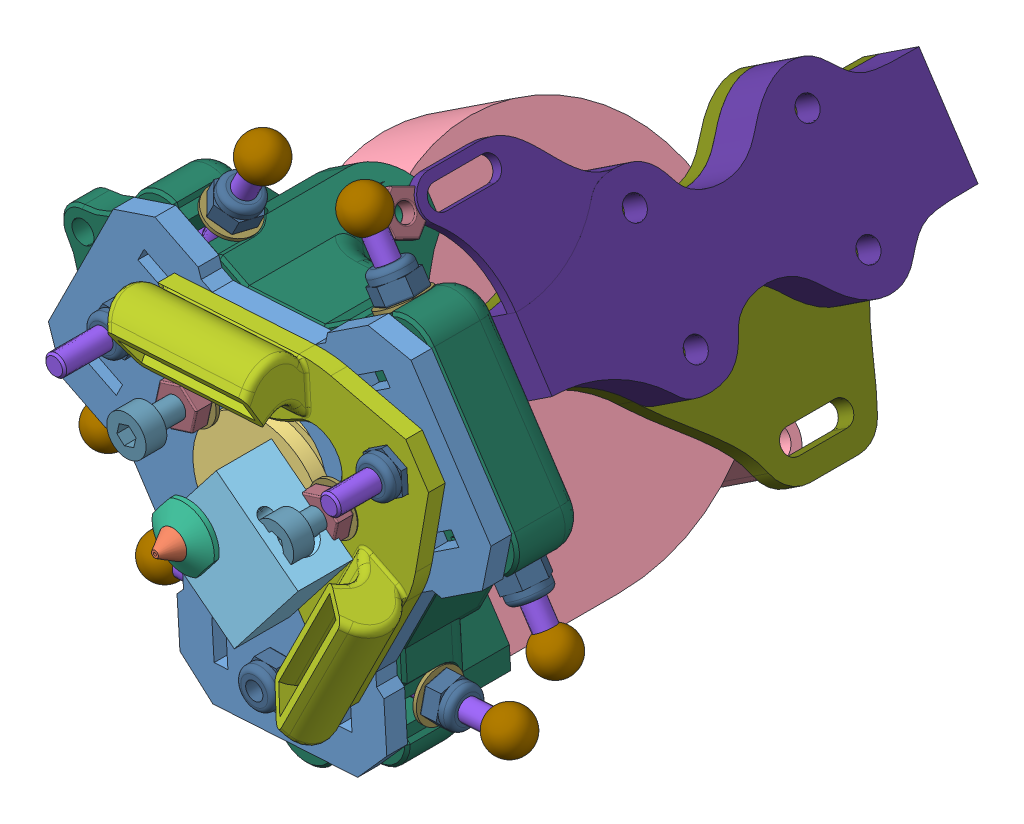
SolidWorks assembly head, configuration Default. Lengths in mm.
Overall size (84.31 86.45 108.8).
49 component instances, 17 part files, 158 mates.
Components (placement in the parent):
- 1223-2: 1223 [Default] at (-3 0 -7.9081) x (-0.551258 0.834335 0) z (0 0 -1) size (64.19 57.24 3)
- 1179-1: 1179 [Default] at (-3 0 -13.9069) x (-1 0 0) z (0 0 1) size (4.4 4.4 23)
- 1136-1: 1136 [Default<As Machined>] at (-3 0 -5.9081) x (0.828844 -0.559479 0) z (0 0 1) size (19 19 18.8)
- 1194-1: 1194 [Default] at (-16.6907 -11.2059 -51.2081) x (0 0 1) z (0.834335 0.551258 0) size (51 51 15)
- heater-block-1: heater-block [Default] at (-3 0 4.2951) x (0.788829 -0.614612 0) z (0 0 -1) size (15 15 8)
- 1180-2: 1180 [Default] at (-3 0 6.4951) x (-0.788829 0.614612 0) z (0 0 1) size (8 9 2.2)
- 1247-1: 1247 [Default] at (-3 0 -7.9081) x (0.551258 -0.834335 0) z (0 0 1) size (51.6 29.13 11.32)
- 242-8: 242 [Default] at (21.7023 4.3356 -15.9081) x (0.722555 0.477403 0.5) z (-0.551258 0.834335 0) size (5.7 5.7 19)
- 242-7: 242 [Default] at (10.6771 21.0223 -15.9081) x (0.698006 0.461183 0.547813) z (0.551258 -0.834335 0) size (5.7 5.7 19)
- 242-9: 242 [Default] at (8.3673 -22.3559 -15.9081) x (0.052165 -0.864453 0.5) z (-0.998184 -0.060235 0) size (5.7 5.7 19)
- 242-10: 242 [Default] at (-11.5964 -23.5606 -15.9081) x (0.052165 -0.864453 -0.5) z (0.998184 0.060235 0) size (5.7 5.7 19)
- 242-11: 242 [Default] at (-28.0444 1.3336 -15.9081) x (0 0 -1) z (0.446927 0.894571 0) size (5.7 5.7 19)
- 242-12: 242 [Default] at (-19.1059 19.225 -15.9081) x (0.774721 -0.38705 -0.5) z (-0.446927 -0.894571 0) size (5.7 5.7 19)
- 1191-1: 1191 [Default] at (2.4083 33.5373 -15.9081) x (0.551258 -0.834335 0) z (0 0 1) size (5.6 6 6)
- 1191-2: 1191 [Default] at (29.9711 -8.1795 -15.9081) x (-0.551258 0.834335 0) z (0.685911 0.453192 0.569336) size (5.6 6 6)
- 1191-3: 1191 [Default] at (-12.402 32.6436 -15.9081) x (-0.446927 -0.894571 0) z (-0.081785 0.04086 0.995812) size (5.6 6 6)
- 1191-4: 1191 [Default] at (-34.7483 -12.085 -15.9081) x (0.446927 0.894571 0) z (0 0 1) size (5.6 6 6)
- 1191-5: 1191 [Default] at (-26.5692 -24.4641 -15.9081) x (0.998184 0.060235 0) z (0 0 1) size (5.6 6 6)
- 1191-6: 1191 [Default] at (23.34 -21.4523 -15.9081) x (-0.998184 -0.060235 0) z (-0.007976 0.132169 0.991195) size (5.6 6 6)
- 204-1: 204 [Default] at (7.9208 25.194 -15.9081) x (-0.799834 -0.528462 -0.284593) z (-0.551258 0.834335 0) size (6.35 5.5 4)
- 204-2: 204 [Default] at (-16.8712 23.6979 -15.9081) x (0.188731 -0.09429 -0.977492) z (0.446927 0.894571 0) size (6.35 5.5 4)
- 204-3: 204 [Default] at (-30.279 -3.1392 -15.9081) x (-0.882358 0.440825 0.164675) z (-0.446927 -0.894571 0) size (6.35 5.5 4)
- 204-4: 204 [Default] at (-16.5873 -23.8618 -15.9081) x (0.059542 -0.986684 0.151356) z (-0.998184 -0.060235 0) size (6.35 5.5 4)
- 204-5: 204 [Default] at (13.3582 -22.0547 -15.9081) x (-0.057745 0.956908 -0.284593) z (0.998184 0.060235 0) size (6.35 5.5 4)
- 204-7: 204 [Default] at (24.4586 0.1639 -15.9081) x (0.566441 0.374256 0.734218) z (0.551258 -0.834335 0) size (6.35 5.5 4)
- 112-2: 112 [Default] at (-32.6899 3.3929 -32.2081) x (-0.535208 0.810044 0.239542) z (-0.834335 -0.551258 0) size (5.7 5.7 28)
- 212-1: 212 [Default] at (-10.4258 18.1031 -32.2081) x (0.051802 -0.078403 -0.995575) z (0.834335 0.551258 0) size (7 7 0.5)
- 258-4: 258 [Default] at (-10.0086 18.3788 -32.2081) x (0.548202 -0.829711 -0.105137) z (0.834335 0.551258 0) size (6.35 5.5 2.4)
- 257-3: 257 [Default] at (8.3082 4.0156 0.1632) x (0.976142 0.217134 0) z (0 0 1) size (5.7 5.7 15)
- 212-3: 212 [Default] at (8.3082 4.0156 -5.9081) size (7 7 0.5)
- 257-4: 257 [Default] at (-12.1317 7.7854 1.0837) x (-0.974821 0.22299 0) z (0 0 1) size (5.7 5.7 15)
- 212-4: 212 [Default] at (-12.1317 7.7854 -5.9081) size (7 7 0.5)
- 242-1: 242 [Default] at (-23.5751 10.2793 -12.9081) x (0.934462 0.356064 0) z (0 0 -1) size (5.7 5.7 19)
- 242-2: 242 [Default] at (16.1897 12.6789 -12.9081) x (-0.951162 0.308691 0) z (0 0 -1) size (5.7 5.7 19)
- 242-3: 242 [Default] at (-1.6146 -22.9582 -21.908) x (0.622999 -0.782222 0) z (0 0 -1) size (5.7 5.7 19)
- 204-8: 204 [Default] at (-1.6146 -22.9582 -7.9081) size (6.35 5.5 4)
- 204-9: 204 [Default] at (16.1897 12.6789 -7.1081) x (0.060235 -0.998184 0) z (0 0 1) size (6.35 5.5 4)
- 204-10: 204 [Default] at (-23.5751 10.2793 -7.9081) size (6.35 5.5 4)
- 258-6: 258 [Default] at (8.3082 4.0156 -3.0081) x (-0.214989 -0.976616 0) z (0 0 -1) size (6.35 5.5 2.4)
- 258-7: 258 [Default] at (-12.1317 7.7854 -3.0081) x (-0.214989 -0.976616 0) z (0 0 -1) size (6.35 5.5 2.4)
- 1301-1: 1301 [Default] at (-3 0 -10.9081) x (-0.551258 0.834335 0) z (0 0 -1) size (65.4 57.84 25.8)
- 212-7: 212 [Default] at (8.1965 24.7768 -15.9081) x (-0.761571 -0.503181 0.408433) z (-0.551258 0.834335 0) size (7 7 0.5)
- 212-8: 212 [Default] at (-17.0947 23.2506 -15.9081) x (-0.091855 0.045891 0.994714) z (0.446927 0.894571 0) size (7 7 0.5)
- 212-9: 212 [Default] at (24.4586 0.1639 -15.9081) x (-0.761571 -0.503181 0.408433) z (-0.551258 0.834335 0) size (7 7 0.5)
- 212-10: 212 [Default] at (13.3582 -22.0547 -15.9081) x (0.048797 -0.808637 -0.586281) z (-0.998184 -0.060235 0) size (7 7 0.5)
- 212-11: 212 [Default] at (-16.0883 -23.8317 -15.9081) x (0.048797 -0.808637 -0.586281) z (-0.998184 -0.060235 0) size (7 7 0.5)
- 212-12: 212 [Default] at (-30.0556 -2.692 -15.9081) x (-0.091855 0.045891 -0.994714) z (-0.446927 -0.894571 0) size (7 7 0.5)
- splitter-base MK2-1: splitter-base MK2 [Default] at (-5.0043 -1.6611 -39.7081) x (0.551258 -0.834335 0) z (0.834335 0.551258 0) size (41.27 60 5.75)
- splitter-base pt 2 MK2-1: splitter-base pt 2 MK2 [Default] at (3.0887 3.6861 -39.7081) x (-0.551258 0.834335 0) z (-0.834335 -0.551258 0) size (36.02 66 7.26)
Mates (geometry in assembly coordinates):
- Coincident71: coincident anti-aligned: plane of ? through (-17.6086 17.054 -13.9081) normal (0 0 -1); plane of ? through (-3 0 -13.9081) normal (0 0 1)
- Coincident72: coincident aligned: plane of ? through (-35.585 3.0772 -10.9081) normal (-0.912788 0.408433 0); plane of ? through (-27.0079 22.2457 -16.9081) normal (-0.912788 0.408433 0)
- Coincident74: coincident anti-aligned: plane of ? through (-17.6086 17.054 -10.9081) normal (0 0 1); plane of 1223-2 through (-2.9839 -0.0222 -10.9081) normal (0 0 -1)
- Coincident75: coincident aligned: plane of ? through (15.9574 26.6808 -10.9081) normal (0.810108 0.586281 0); plane of 1223-2
- Coincident76: coincident aligned: plane of ? through (15.7122 -8.3729 -10.9081) normal (0.912788 -0.408433 0); plane of 1223-2
- Concentric95: concentric anti-aligned: cylinder of ? through (-3 0 -13.9081) axis (0 0 -1) radius 8.5; cylinder of 1136-1 through (-3 0 -5.9081) axis (0 0 1) radius 1.65
- Coincident78: coincident anti-aligned: plane of 1223-2 through (-3 0 -7.9081) normal (0 0 1); plane of 1136-1 through (4.874 -5.3151 -7.9081) normal (0 0 -1)
- Concentric96: concentric aligned: cylinder of 1179-1 through (-3 0 -13.9069) axis (0 0 1) radius 2; cylinder of 1136-1 through (-3 0 -5.9081) axis (0 0 1) radius 9.5
- Coincident77: coincident aligned: plane of 1179-1 through (-4.35 0 -5.9081) normal (0 0 1); plane of 1136-1 through (-1.6324 -0.9231 -5.9081) normal (0 0 1)
- Coincident80: coincident anti-aligned: plane of ? through (-3 0 -16.9081) normal (0 0 -1); plane of ? through (-12.0348 -13.8173 -16.9081) normal (0 0 1)
- Coincident82: coincident anti-aligned: plane of 1194-1; plane of ? through (1.5559 -33.1547 37.943) normal (-0.912788 0.408433 0)
- Coincident83: coincident anti-aligned: plane of 1194-1 through (1.5559 -33.1547 -19.5081) normal (0 0 1); plane of ? through (-12.0348 -13.8173 -19.5081) normal (0 0 -1)
- Concentric99: concentric anti-aligned: cylinder of ? through (11.9207 1.5402 -13.9081) axis (0 0 -1) radius 1.5; cylinder of ? through (11.9207 1.5402 -36.9081) axis (0 0 1) radius 1.6
- Coincident86: coincident anti-aligned: plane of 1194-1; plane of ? through (1.5559 -33.1547 37.943) normal (0.408433 0.912788 0)
- Concentric100: concentric aligned: cylinder of 1179-1 through (-3 0 -13.9069) axis (0 0 1) radius 2; cylinder of heater-block-1 through (-3 0 -3.7049) axis (0 0 1) radius 1.65
- Concentric101: concentric aligned: cylinder of 1179-1 through (-3 0 -13.9069) axis (0 0 1) radius 2; cylinder of 1180-2 through (-3 0 6.4951) axis (0 0 1) radius 1.65
- Coincident87: coincident anti-aligned: plane of heater-block-1 through (-3 0 4.2951) normal (0 0 1); plane of 1180-2 through (-6.5497 2.7658 4.2951) normal (0 0 -1)
- Coincident88: coincident aligned: circle of 1179-1; plane of 1180-2 through (-4.5777 1.2292 6.4951) normal (0 0 1)
- Parallel2: parallel aligned: plane of heater-block-1 through (-8.1322 -1.7059 -3.7049) normal (-0.788829 0.614612 0); plane of 1180-2 through (-8.2818 -0.2708 6.4951) normal (-0.788829 0.614612 0)
- Coincident89: coincident: plane of 1179-1; plane of assembly through (0 0 0) normal (0 1 0)
- Parallel4: parallel aligned: plane of ? through (15.7122 -8.3729 -10.9081) normal (0.912788 -0.408433 0); plane of ? through (2.1107 -34.608 -36.9081) normal (0.912788 -0.408433 0)
- Coincident92: coincident anti-aligned: plane of ? through (-3 0 -16.9081) normal (0 0 -1); plane of ? through (-10.8759 3.5241 -16.9081) normal (0 0 1)
- Concentric104: concentric anti-aligned: cylinder of ? through (-23.9941 9.394 -16.9081) axis (0 0 1) radius 1.5; cylinder of ? through (-23.9941 9.394 -16.9081) axis (0 0 -1) radius 1.5
- Concentric105: concentric aligned: cylinder of 1136-1 through (-3 0 -5.9081) axis (0 0 1) radius 8.5; cylinder of ? through (-3 0 -18.3081) axis (0 0 1) radius 8.7
- Coincident93: coincident anti-aligned: plane of 1223-2 through (-3 0 -7.9081) normal (0 0 1); plane of 1247-1 through (17.3484 -0.6643 -7.9081) normal (0 0 -1)
- Concentric108: concentric aligned: cylinder of ? through (-37.3498 -20.4539 -12.4081) axis (0.408433 0.912788 0) radius 0.2; cylinder of 242-7 through (-34.6134 -14.3385 -12.4081) axis (0.408433 0.912788 0) radius 1.5
- Coincident94: coincident anti-aligned: plane of ? through (-25.6139 -0.8367 -10.9081) normal (0.408433 0.912788 0); plane of 242-7
- Concentric109: concentric anti-aligned: cylinder of ? through (-37.3498 -20.4539 -12.4081) axis (0.408433 0.912788 0) radius 0.2; cylinder of 242-8 through (-13.3749 33.1265 -12.4081) axis (-0.408433 -0.912788 0) radius 1.5
- Coincident95: coincident anti-aligned: plane of ? through (-17.4453 17.4191 -10.9081) normal (-0.408433 -0.912788 0); plane of 242-8
- Concentric110: concentric aligned: cylinder of ? through (-9.6929 48.4784 -12.4081) axis (0.586281 -0.810108 0) radius 0.2; cylinder of 242-9 through (0.3892 34.5473 -12.4081) axis (0.586281 -0.810108 0) radius 1.5
- Coincident96: coincident anti-aligned: plane of ? through (11.957 23.1685 -10.9081) normal (0.586281 -0.810108 0); plane of 242-9
- Concentric111: concentric anti-aligned: cylinder of ? through (-9.6929 48.4784 -12.4081) axis (0.586281 -0.810108 0) radius 0.2; cylinder of 242-10 through (30.8758 -7.5783 -12.4081) axis (-0.586281 0.810108 0) radius 1.5
- Coincident97: coincident anti-aligned: plane of ? through (23.6826 6.9664 -10.9081) normal (-0.586281 0.810108 0); plane of 242-10
- Concentric112: concentric aligned: cylinder of ? through (38.7491 -18.8126 -12.4081) axis (-0.994714 -0.102681 0) radius 0.2; cylinder of 242-11 through (25.2242 -20.2087 -12.4081) axis (-0.994714 -0.102681 0) radius 1.5
- Coincident98: coincident anti-aligned: plane of ? through (9.586 -24.5374 -10.9081) normal (-0.994714 -0.102681 0); plane of 242-11
- Concentric113: concentric anti-aligned: cylinder of ? through (38.7491 -18.8126 -12.4081) axis (-0.994714 -0.102681 0) radius 0.2; cylinder of 242-12 through (-26.5009 -25.5481 -12.4081) axis (0.994714 0.102681 0) radius 1.5
- Coincident99: coincident anti-aligned: plane of ? through (-10.8627 -21.2195 -10.9081) normal (0.994714 0.102681 0); plane of 242-12
- Concentric114: concentric aligned: cylinder of 242-7 through (1.857 34.3716 -15.9081) axis (0.551258 -0.834335 0) radius 1.5; cylinder of 1191-1 through (4.062 31.0343 -15.9081) axis (0.551258 -0.834335 0) radius 1.25
- Coincident100: coincident anti-aligned: plane of 242-7 through (1.857 34.3716 -15.9081) normal (-0.551258 0.834335 0); circle of 1191-1
- Concentric115: concentric aligned: cylinder of 242-12 through (-11.955 33.5381 -15.9081) axis (-0.446927 -0.894571 0) radius 1.5; cylinder of 1191-3 through (-13.7427 29.9599 -15.9081) axis (-0.446927 -0.894571 0) radius 1.25
- Coincident101: coincident anti-aligned: plane of 242-12 through (-11.955 33.5381 -15.9081) normal (0.446927 0.894571 0); circle of 1191-3
- Concentric116: concentric aligned: cylinder of 242-11 through (-35.1952 -12.9795 -15.9081) axis (0.446927 0.894571 0) radius 1.5; cylinder of 1191-4 through (-33.4075 -9.4012 -15.9081) axis (0.446927 0.894571 0) radius 1.25
- Coincident102: coincident anti-aligned: plane of 242-11 through (-35.1952 -12.9795 -15.9081) normal (-0.446927 -0.894571 0); circle of 1191-4
- Concentric117: concentric aligned: cylinder of 242-10 through (-27.5674 -24.5244 -15.9081) axis (0.998184 0.060235 0) radius 1.5; cylinder of 1191-5 through (-23.5746 -24.2834 -15.9081) axis (0.998184 0.060235 0) radius 1.25
- Coincident103: coincident anti-aligned: plane of 242-10 through (-27.5674 -24.5244 -15.9081) normal (-0.998184 -0.060235 0); circle of 1191-5
- Concentric118: concentric aligned: cylinder of 242-9 through (24.3382 -21.3921 -15.9081) axis (-0.998184 -0.060235 0) radius 1.5; cylinder of 1191-6 through (20.3455 -21.6331 -15.9081) axis (-0.998184 -0.060235 0) radius 1.25
- Coincident104: coincident anti-aligned: plane of 242-9 through (24.3382 -21.3921 -15.9081) normal (0.998184 0.060235 0); circle of 1191-6
- Concentric119: concentric aligned: cylinder of 242-8 through (30.5224 -9.0138 -15.9081) axis (-0.551258 0.834335 0) radius 1.5; cylinder of 1191-2 through (28.3174 -5.6764 -15.9081) axis (-0.551258 0.834335 0) radius 1.25
- Coincident105: coincident anti-aligned: plane of 242-8 through (30.5224 -9.0138 -15.9081) normal (0.551258 -0.834335 0); circle of 1191-2
- Concentric120: concentric aligned: cylinder of 242-7 through (1.857 34.3716 -15.9081) axis (0.551258 -0.834335 0) radius 1.5; cylinder of 204-1 through (6.5978 27.1964 -15.9081) axis (0.551258 -0.834335 0) radius 1.25
- Coincident111: coincident anti-aligned: plane of ? through (-31.4442 -3.7056 -10.9081) normal (-0.408433 -0.912788 0); plane of 204-1
- Concentric121: concentric aligned: cylinder of 242-12 through (-11.955 33.5381 -15.9081) axis (-0.446927 -0.894571 0) radius 1.5; cylinder of 204-2 through (-15.7986 25.8448 -15.9081) axis (-0.446927 -0.894571 0) radius 1.25
- Coincident112: coincident anti-aligned: plane of ? through (-15.7079 -22.9763 -10.9081) normal (-0.994714 -0.102681 0); plane of 204-2
- Concentric122: concentric aligned: cylinder of 242-11 through (-35.1952 -12.9795 -15.9081) axis (0.446927 0.894571 0) radius 1.5; cylinder of 204-3 through (-31.3516 -5.2862 -15.9081) axis (0.446927 0.894571 0) radius 1.25
- Coincident113: coincident anti-aligned: plane of ? through (14.1335 -19.8959 -10.9081) normal (0.994714 0.102681 0); plane of 204-3
- Concentric123: concentric aligned: cylinder of 242-10 through (-27.5674 -24.5244 -15.9081) axis (0.998184 0.060235 0) radius 1.5; cylinder of 204-4 through (-18.983 -24.0063 -15.9081) axis (0.998184 0.060235 0) radius 1.25
- Coincident114: coincident anti-aligned: plane of ? through (23.252 0.4827 -10.9081) normal (0.586281 -0.810108 0); plane of 204-4
- Concentric124: concentric aligned: cylinder of 242-9 through (24.3382 -21.3921 -15.9081) axis (-0.998184 -0.060235 0) radius 1.5; cylinder of 204-5 through (15.7538 -21.9101 -15.9081) axis (-0.998184 -0.060235 0) radius 1.25
- Coincident115: coincident anti-aligned: plane of ? through (5.6636 24.786 -10.9081) normal (-0.586281 0.810108 0); plane of 204-5
- Concentric125: concentric aligned: cylinder of 242-8 through (30.5224 -9.0138 -15.9081) axis (-0.551258 0.834335 0) radius 1.5; cylinder of 204-7 through (25.7816 -1.8385 -15.9081) axis (-0.551258 0.834335 0) radius 1.25
- Coincident116: coincident anti-aligned: plane of ? through (-19.1912 23.678 -10.9081) normal (0.408433 0.912788 0); plane of 204-7
- Concentric126: concentric aligned: cylinder of 1194-1 through (-15.7521 14.584 -32.2081) axis (-0.834335 -0.551258 0) radius 2.1; cylinder of 112-2 through (-11.8315 17.1743 -32.2081) axis (-0.834335 -0.551258 0) radius 1.5
- Coincident117: coincident anti-aligned: plane of ? through (2.839 16.477 -31.7081) normal (-0.912788 0.408433 0); plane of 112-2
- Coincident118: coincident anti-aligned: plane of 1194-1; plane of ? through (-32.0838 -9.8724 -32.4713) normal (0.240121 -0.970743 0)
- Concentric127: concentric anti-aligned: cylinder of ? through (-19.5349 -13.1037 -32.2081) axis (-0.240121 0.970743 0) radius 2.3; cylinder of 112-2 through (-22.6403 -0.5493 -32.2081) axis (0.240121 -0.970743 0) radius 1.5
- Concentric128: concentric aligned: cylinder of 1194-1 through (19.7596 2.9514 -70.2081) axis (0.240121 -0.970743 0) radius 2.1; cylinder of ? through (17.3584 12.6588 -70.2081) axis (0.240121 -0.970743 0) radius 1.5
- Coincident119: coincident anti-aligned: plane of 1194-1; plane of ? through (23.3614 -11.6097 -70.2081) normal (-0.240121 0.970743 0)
- Coincident120: coincident anti-aligned: plane of 1194-1; plane of ? through (8.0295 -18.687 -60.2081) normal (-0.912788 0.408433 0)
- Concentric129: concentric anti-aligned: cylinder of ? through (-1.8114 -25.6225 -65.0081) axis (0.912788 -0.408433 0) radius 2.3; cylinder of ? through (12.9301 -32.2186 -65.0081) axis (-0.912788 0.408433 0) radius 1.5
- Coincident121: coincident anti-aligned: plane of ? through (-33.0082 -6.1351 -32.4713) normal (-0.240121 0.970743 0); plane of 212-1
- Concentric130: concentric aligned: cylinder of 112-2 through (-11.8315 17.1743 -32.2081) axis (-0.834335 -0.551258 0) radius 1.5; cylinder of 212-1 through (-10.0086 18.3788 -32.2081) axis (-0.834335 -0.551258 0) radius 1.6
- Coincident122: coincident anti-aligned: plane of 212-1 through (-10.0086 18.3788 -32.2081) normal (0.834335 0.551258 0); plane of 258-4 through (-10.0086 18.3788 -32.2081) normal (-0.834335 -0.551258 0)
- Concentric131: concentric aligned: cylinder of 112-2 through (-11.8315 17.1743 -32.2081) axis (-0.834335 -0.551258 0) radius 1.5; cylinder of 258-4 through (-8.0062 19.7018 -32.2081) axis (-0.834335 -0.551258 0) radius 1.25
- Concentric133: concentric aligned: cylinder of ? through (17.3584 12.6588 -70.2081) axis (0.240121 -0.970743 0) radius 1.5; cylinder of ? through (18.1388 9.5039 -70.2081) axis (0.240121 -0.970743 0) radius 1.25
- Concentric134: concentric anti-aligned: cylinder of 257-3 through (8.3082 4.0156 -11.8368) axis (0 0 1) radius 1.5; cylinder of 212-3 through (8.3082 4.0156 -5.4081) axis (0 0 -1) radius 1.6
- Coincident126: coincident anti-aligned: plane of 1136-1 through (-1.6324 -0.9231 -5.9081) normal (0 0 1); plane of 212-3 through (8.3082 4.0156 -5.9081) normal (0 0 -1)
- Concentric135: concentric anti-aligned: cylinder of 1223-2 through (8.3082 4.0156 -7.9081) axis (0 0 -1) radius 1.475; cylinder of 257-3 through (8.3082 4.0156 -11.8368) axis (0 0 1) radius 1.5
- Concentric136: concentric anti-aligned: cylinder of 257-4 through (-12.1317 7.7854 -10.9163) axis (0 0 1) radius 1.5; cylinder of 212-4 through (-12.1317 7.7854 -5.4081) axis (0 0 -1) radius 1.6
- Coincident128: coincident anti-aligned: plane of 1136-1 through (-1.6324 -0.9231 -5.9081) normal (0 0 1); plane of 212-4 through (-12.1317 7.7854 -5.9081) normal (0 0 -1)
- Concentric137: concentric anti-aligned: cylinder of 1223-2 through (-12.1317 7.7854 -7.9081) axis (0 0 -1) radius 1.475; cylinder of 257-4 through (-12.1317 7.7854 -10.9163) axis (0 0 1) radius 1.5
- Concentric138: concentric anti-aligned: cylinder of ? through (-0.6383 -22.8784 -16.9081) axis (0 0 1) radius 1.5; cylinder of 242-1 through (-0.6383 -22.8784 -2.1081) axis (0 0 -1) radius 1.5
- Coincident130: coincident anti-aligned: plane of ? through (-3 0 -12.9081) normal (0 0 -1); plane of 242-1 through (-19.5744 -15.9464 -12.9081) normal (0 0 1)
- Coincident131: coincident anti-aligned: plane of ? through (-10.8759 3.5241 -12.9081) normal (0 0 -1); plane of 242-2 through (-8.5228 22.3271 -12.9081) normal (0 0 1)
- Concentric139: concentric anti-aligned: cylinder of ? through (-23.9941 9.394 -16.9081) axis (0 0 1) radius 1.5; cylinder of 242-2 through (-23.9941 9.394 -3.3081) axis (0 0 -1) radius 1.5
- Coincident132: coincident anti-aligned: plane of ? through (-3 0 -16.9081) normal (0 0 -1); plane of 242-3 through (15.6325 13.4845 -16.9081) normal (0 0 1)
- Concentric140: concentric anti-aligned: cylinder of ? through (15.6325 13.4845 -16.9081) axis (0 0 1) radius 1.5; cylinder of 242-3 through (15.6325 13.4845 -0.9081) axis (0 0 -1) radius 1.5
- Coincident133: coincident anti-aligned: plane of ? through (-12.0348 -13.8173 -19.5081) normal (0 0 -1); plane of ? through (11.9207 1.5402 -19.5081) normal (0 0 1)
- Concentric141: concentric anti-aligned: cylinder of ? through (11.9207 1.5402 -31.7081) axis (0 0 1) radius 1.6; cylinder of ? through (11.9207 1.5402 0.4919) axis (0 0 -1) radius 1.5
- Coincident134: coincident anti-aligned: plane of 1223-2 through (-3 0 -7.9081) normal (0 0 1); plane of ? through (11.9207 1.5402 -7.9081) normal (0 0 -1)
- Concentric142: concentric aligned: cylinder of ? through (11.9207 1.5402 0.4919) axis (0 0 -1) radius 1.5; cylinder of ? through (11.9207 1.5402 -5.5081) axis (0 0 -1) radius 1.25
- Coincident135: coincident anti-aligned: plane of 1223-2 through (-3 0 -7.9081) normal (0 0 1); plane of 204-8 through (-1.6146 -22.9582 -7.9081) normal (0 0 -1)
- Concentric143: concentric aligned: cylinder of 242-3 through (-1.6146 -22.9582 -5.908) axis (0 0 -1) radius 1.5; cylinder of 204-8 through (-1.6146 -22.9582 -5.5081) axis (0 0 -1) radius 1.25
- Concentric144: concentric aligned: cylinder of 242-2 through (16.1897 12.6789 3.0919) axis (0 0 -1) radius 1.5; cylinder of 204-9 through (16.1897 12.6789 -4.7081) axis (0 0 -1) radius 1.25
- Coincident137: coincident anti-aligned: plane of 1223-2 through (-3 0 -7.9081) normal (0 0 1); plane of 204-10 through (-23.5751 10.2793 -7.9081) normal (0 0 -1)
- Concentric145: concentric aligned: cylinder of 242-1 through (-23.5751 10.2793 3.0919) axis (0 0 -1) radius 1.5; cylinder of 204-10 through (-23.5751 10.2793 -5.5081) axis (0 0 -1) radius 1.25
- Parallel15: parallel anti-aligned: plane of 1247-1 through (13.4922 10.8966 -7.1081) normal (0.446927 0.894571 0); plane of 204-9 through (13.5403 10.9284 -4.7081) normal (-0.446927 -0.894571 0)
- Coincident138: coincident anti-aligned: plane of 1247-1 through (-3 0 -7.1081) normal (0 0 1); plane of 204-9 through (16.1897 12.6789 -7.1081) normal (0 0 -1)
- Coincident140: coincident anti-aligned: plane of ? through (-3 0 -16.9081) normal (0 0 -1); plane of ? through (-12.4899 7.3445 -16.9081) normal (0 0 1)
- Concentric146: concentric aligned: cylinder of ? through (-12.4899 7.3445 -13.9081) axis (0 0 -1) radius 1.4; cylinder of ? through (-12.4899 7.3445 -16.9081) axis (0 0 -1) radius 1.6
- Coincident141: coincident aligned: plane of 257-3; plane of ? through (-12.4899 7.3445 -17.4081) normal (0 0 -1)
- Coincident142: coincident anti-aligned: plane of ? through (-3 0 -16.9081) normal (0 0 -1); plane of ? through (-4.6156 -11.8907 -16.9081) normal (0 0 1)
- Concentric147: concentric aligned: cylinder of ? through (-4.6156 -11.8907 -13.9081) axis (0 0 -1) radius 1.4; cylinder of ? through (-4.6156 -11.8907 -16.9081) axis (0 0 -1) radius 1.6
- Coincident143: coincident aligned: plane of 257-4 through (-12.1317 7.7854 1.0837) normal (0 0 -1); plane of ? through (-4.6156 -11.8907 1.0837) normal (0 0 -1)
- Coincident144: coincident anti-aligned: plane of 212-3 through (8.3082 4.0156 -5.4081) normal (0 0 1); plane of 258-6 through (8.3082 4.0156 -5.4081) normal (0 0 -1)
- Concentric148: concentric aligned: cylinder of 257-3 through (8.3082 4.0156 -11.8368) axis (0 0 1) radius 1.5; cylinder of 258-6 through (8.3082 4.0156 -5.4081) axis (0 0 1) radius 1.25
- Coincident146: coincident anti-aligned: plane of 212-4 through (-12.1317 7.7854 -5.4081) normal (0 0 1); plane of 258-7 through (-12.1317 7.7854 -5.4081) normal (0 0 -1)
- Concentric149: concentric aligned: cylinder of 257-4 through (-12.1317 7.7854 -10.9163) axis (0 0 1) radius 1.5; cylinder of 258-7 through (-12.1317 7.7854 -5.4081) axis (0 0 1) radius 1.25
- Coincident148: coincident aligned: plane of ? through (15.9574 26.6808 -10.9081) normal (0.810108 0.586281 0); plane of ? through (28.2693 9.6686 -16.9081) normal (0.810108 0.586281 0)
- Coincident149: coincident anti-aligned: plane of 1223-2 through (-3 0 -10.9081) normal (0 0 -1); plane of 1301-1 through (13.3217 23.3688 -10.9081) normal (0 0 1)
- Concentric150: concentric anti-aligned: cylinder of 242-3 through (-1.6146 -22.9582 -5.908) axis (0 0 -1) radius 1.5; cylinder of 1301-1 through (-1.6146 -22.9582 -24.7081) axis (0 0 1) radius 1.7
- Concentric151: concentric anti-aligned: cylinder of 242-1 through (-23.5751 10.2793 3.0919) axis (0 0 -1) radius 1.5; cylinder of 1301-1 through (-23.5751 10.2793 -24.7081) axis (0 0 1) radius 1.7
- Concentric152: concentric aligned: cylinder of 1247-1 through (16.1897 12.6789 6.4058) axis (0 0 -1) radius 1.7; cylinder of 242-2 through (16.1897 12.6789 3.0919) axis (0 0 -1) radius 1.5
- Concentric153: concentric anti-aligned: cylinder of 242-8 through (30.5224 -9.0138 -15.9081) axis (-0.551258 0.834335 0) radius 1.5; cylinder of 212-9 through (24.1829 0.5811 -15.9081) axis (0.551258 -0.834335 0) radius 1.6
- Coincident151: coincident anti-aligned: plane of 1301-1 through (24.1829 0.5811 -15.9081) normal (0.551258 -0.834335 0); plane of 212-9 through (24.1829 0.5811 -15.9081) normal (-0.551258 0.834335 0)
- Concentric154: concentric anti-aligned: cylinder of 242-9 through (24.3382 -21.3921 -15.9081) axis (-0.998184 -0.060235 0) radius 1.5; cylinder of 212-10 through (12.8591 -22.0848 -15.9081) axis (0.998184 0.060235 0) radius 1.6
- Coincident152: coincident anti-aligned: plane of 1301-1 through (12.8591 -22.0848 -15.9081) normal (0.998184 0.060235 0); plane of 212-10 through (12.8591 -22.0848 -15.9081) normal (-0.998184 -0.060235 0)
- Concentric155: concentric aligned: cylinder of 242-8 through (30.5224 -9.0138 -15.9081) axis (-0.551258 0.834335 0) radius 1.5; cylinder of 1301-1 through (34.2157 -14.6036 -15.9081) axis (-0.551258 0.834335 0) radius 1.6
- Concentric156: concentric anti-aligned: cylinder of 242-9 through (24.3382 -21.3921 -15.9081) axis (-0.998184 -0.060235 0) radius 1.5; cylinder of 1301-1 through (-41.1395 -25.3434 -15.9081) axis (0.998184 0.060235 0) radius 1.6
- Coincident153: coincident anti-aligned: plane of 1301-1 through (-16.0883 -23.8317 -15.9081) normal (-0.998184 -0.060235 0); plane of 212-11 through (-16.0883 -23.8317 -15.9081) normal (0.998184 0.060235 0)
- Concentric157: concentric aligned: cylinder of 242-10 through (-27.5674 -24.5244 -15.9081) axis (0.998184 0.060235 0) radius 1.5; cylinder of 212-11 through (-16.5873 -23.8618 -15.9081) axis (0.998184 0.060235 0) radius 1.6
- Concentric158: concentric aligned: cylinder of 242-10 through (-27.5674 -24.5244 -15.9081) axis (0.998184 0.060235 0) radius 1.5; cylinder of 1301-1 through (-41.1395 -25.3434 -15.9081) axis (0.998184 0.060235 0) radius 1.6
- Coincident154: coincident anti-aligned: plane of 1301-1 through (-30.0556 -2.692 -15.9081) normal (-0.446927 -0.894571 0); plane of 212-12 through (-30.0556 -2.692 -15.9081) normal (0.446927 0.894571 0)
- Concentric159: concentric aligned: cylinder of 242-11 through (-35.1952 -12.9795 -15.9081) axis (0.446927 0.894571 0) radius 1.5; cylinder of 212-12 through (-30.279 -3.1392 -15.9081) axis (0.446927 0.894571 0) radius 1.6
- Concentric160: concentric anti-aligned: cylinder of 242-11 through (-35.1952 -12.9795 -15.9081) axis (0.446927 0.894571 0) radius 1.5; cylinder of 1301-1 through (-4.2694 48.9217 -15.9081) axis (-0.446927 -0.894571 0) radius 1.6
- Coincident155: coincident anti-aligned: plane of 1301-1 through (8.1965 24.7768 -15.9081) normal (-0.551258 0.834335 0); plane of 212-7 through (8.1965 24.7768 -15.9081) normal (0.551258 -0.834335 0)
- Concentric161: concentric aligned: cylinder of 242-7 through (1.857 34.3716 -15.9081) axis (0.551258 -0.834335 0) radius 1.5; cylinder of 212-7 through (7.9208 25.194 -15.9081) axis (0.551258 -0.834335 0) radius 1.6
- Concentric162: concentric anti-aligned: cylinder of 242-7 through (1.857 34.3716 -15.9081) axis (0.551258 -0.834335 0) radius 1.5; cylinder of 1301-1 through (34.2157 -14.6036 -15.9081) axis (-0.551258 0.834335 0) radius 1.6
- Coincident156: coincident anti-aligned: plane of 1301-1 through (-17.0947 23.2506 -15.9081) normal (0.446927 0.894571 0); plane of 212-8 through (-17.0947 23.2506 -15.9081) normal (-0.446927 -0.894571 0)
- Concentric163: concentric aligned: cylinder of 242-12 through (-11.955 33.5381 -15.9081) axis (-0.446927 -0.894571 0) radius 1.5; cylinder of 212-8 through (-16.8712 23.6979 -15.9081) axis (-0.446927 -0.894571 0) radius 1.6
- Concentric164: concentric aligned: cylinder of 242-12 through (-11.955 33.5381 -15.9081) axis (-0.446927 -0.894571 0) radius 1.5; cylinder of 1301-1 through (-4.2694 48.9217 -15.9081) axis (-0.446927 -0.894571 0) radius 1.6
- Concentric165: concentric anti-aligned: cylinder of 1223-2 through (-23.5751 10.2793 -10.9081) axis (0 0 1) radius 1.5; cylinder of 242-1 through (-23.5751 10.2793 3.0919) axis (0 0 -1) radius 1.5
- Coincident157: coincident anti-aligned: plane of 242-8 through (21.7023 4.3356 -15.9081) normal (0.551258 -0.834335 0); plane of 1301-1 through (2.5126 -8.3434 -10.9081) normal (-0.551258 0.834335 0)
- Coincident158: coincident anti-aligned: plane of 242-7 through (10.6771 21.0223 -15.9081) normal (-0.551258 0.834335 0); plane of 1301-1 through (-8.5126 8.3434 -10.9081) normal (0.551258 -0.834335 0)
- Concentric166: concentric anti-aligned: cylinder of 242-2 through (16.1897 12.6789 3.0919) axis (0 0 -1) radius 1.5; cylinder of 1301-1 through (16.1897 12.6789 -24.7081) axis (0 0 1) radius 1.7
- Coincident159: coincident anti-aligned: plane of 242-2 through (16.1897 12.6789 -12.9081) normal (0 0 1); plane of 1301-1 through (13.3217 23.3688 -12.9081) normal (0 0 -1)
- Coincident160: coincident anti-aligned: plane of 242-12 through (-19.1059 19.225 -15.9081) normal (0.446927 0.894571 0); plane of 1301-1 through (1.4693 8.9457 -10.9081) normal (-0.446927 -0.894571 0)
- Coincident161: coincident anti-aligned: plane of 242-11 through (-28.0444 1.3336 -15.9081) normal (-0.446927 -0.894571 0); plane of 1301-1 through (-7.4693 -8.9457 -10.9081) normal (0.446927 0.894571 0)
- Coincident162: coincident anti-aligned: plane of 242-1 through (-23.5751 10.2793 -12.9081) normal (0 0 1); plane of 1301-1 through (13.3217 23.3688 -12.9081) normal (0 0 -1)
- Coincident163: coincident anti-aligned: plane of 242-10 through (-11.5964 -23.5606 -15.9081) normal (-0.998184 -0.060235 0); plane of 1301-1 through (-12.9818 -0.6024 -10.9081) normal (0.998184 0.060235 0)
- Coincident164: coincident anti-aligned: plane of 242-9 through (8.3673 -22.3559 -15.9081) normal (0.998184 0.060235 0); plane of 1301-1 through (6.9818 0.6024 -10.9081) normal (-0.998184 -0.060235 0)
- Concentric167: concentric anti-aligned: cylinder of 1136-1 through (-3 0 -5.9081) axis (0 0 1) radius 8.5; cylinder of 1301-1 through (-3 0 -10.9081) axis (0 0 -1) radius 8.7
- Concentric168: concentric anti-aligned: cylinder of 1223-2 through (16.1897 12.6789 -10.9081) axis (0 0 1) radius 1.5; cylinder of 242-2 through (16.1897 12.6789 3.0919) axis (0 0 -1) radius 1.5
- Coincident165: coincident anti-aligned: plane of 1194-1 through (10.4326 -25.047 -24.7081) normal (0 0 1); plane of 1301-1 through (13.3217 23.3688 -24.7081) normal (0 0 -1)
- Coincident166: coincident anti-aligned: plane of 1194-1 through (-16.6907 -11.2059 -51.2081) normal (-0.834335 -0.551258 0); plane of 1301-1 through (-20.7201 -5.1074 -36.7081) normal (0.834335 0.551258 0)
- Coincident167: coincident anti-aligned: plane of 1194-1 through (10.4326 -25.047 -24.7081) normal (0.551258 -0.834335 0); plane of 1301-1 through (-2.0824 -33.3158 -27.7081) normal (-0.551258 0.834335 0)
- Coincident168: coincident anti-aligned: plane of 204-3 through (-30.279 -3.1392 -15.9081) normal (0.446927 0.894571 0); plane of 212-12 through (-30.279 -3.1392 -15.9081) normal (-0.446927 -0.894571 0)
- Coincident169: coincident anti-aligned: plane of 204-1 through (7.9208 25.194 -15.9081) normal (0.551258 -0.834335 0); plane of 212-7 through (7.9208 25.194 -15.9081) normal (-0.551258 0.834335 0)
- Coincident170: coincident anti-aligned: plane of 204-7 through (24.4586 0.1639 -15.9081) normal (-0.551258 0.834335 0); plane of 212-9 through (24.4586 0.1639 -15.9081) normal (0.551258 -0.834335 0)
- Coincident171: coincident anti-aligned: plane of 204-5 through (13.3582 -22.0547 -15.9081) normal (-0.998184 -0.060235 0); plane of 212-10 through (13.3582 -22.0547 -15.9081) normal (0.998184 0.060235 0)
- Coincident172: coincident anti-aligned: plane of 204-4 through (-16.5873 -23.8618 -15.9081) normal (0.998184 0.060235 0); plane of 212-11 through (-16.5873 -23.8618 -15.9081) normal (-0.998184 -0.060235 0)
- Coincident173: coincident anti-aligned: plane of 204-2 through (-16.8712 23.6979 -15.9081) normal (-0.446927 -0.894571 0); plane of 212-8 through (-16.8712 23.6979 -15.9081) normal (0.446927 0.894571 0)
- Parallel16: parallel aligned: plane of 1223-2 through (-4.2334 20.4391 -10.9081) normal (-0.060235 0.998184 0); plane of 1247-1 through (3.2252 20.8929 -5.5081) normal (-0.060235 0.998184 0)
- Concentric169: concentric anti-aligned: cylinder of 1136-1 through (-3 0 -5.9081) axis (0 0 1) radius 1.65; cylinder of 1301-1 through (-3 0 -10.9081) axis (0 0 -1) radius 8.7
- Parallel17: parallel anti-aligned: plane of 1194-1 through (-4.1757 -2.9371 -51.2081) normal (0.834335 0.551258 0); plane of splitter-base MK2-1 through (-5.0043 -1.6611 -39.7081) normal (-0.834335 -0.551258 0)
- Distance1: distance = 15 mm anti-aligned: plane of splitter-base MK2-1 through (-11.0205 12.3423 -39.7081) normal (0 0 1); plane of 1136-1 through (4.0452 -4.7556 -24.7081) normal (0 0 -1)
- Coincident176: coincident anti-aligned: plane of splitter-base MK2-1 through (-2.7516 -0.1727 -39.7081) normal (0.834335 0.551258 0); plane of splitter-base pt 2 MK2-1 through (-2.7516 -0.1727 -39.7081) normal (-0.834335 -0.551258 0)
- Concentric170: concentric anti-aligned: cylinder of splitter-base MK2-1 through (1.1817 12.0146 -58.7081) axis (-0.834335 -0.551258 0) radius 1.6; cylinder of splitter-base pt 2 MK2-1 through (-15.505 0.9894 -58.7081) axis (0.834335 0.551258 0) radius 1.6
- Concentric171: concentric anti-aligned: cylinder of splitter-base MK2-1 through (10.0018 -1.3348 -83.7081) axis (-0.834335 -0.551258 0) radius 1.6; cylinder of splitter-base pt 2 MK2-1 through (-6.6849 -12.3599 -83.7081) axis (0.834335 0.551258 0) radius 1.6
